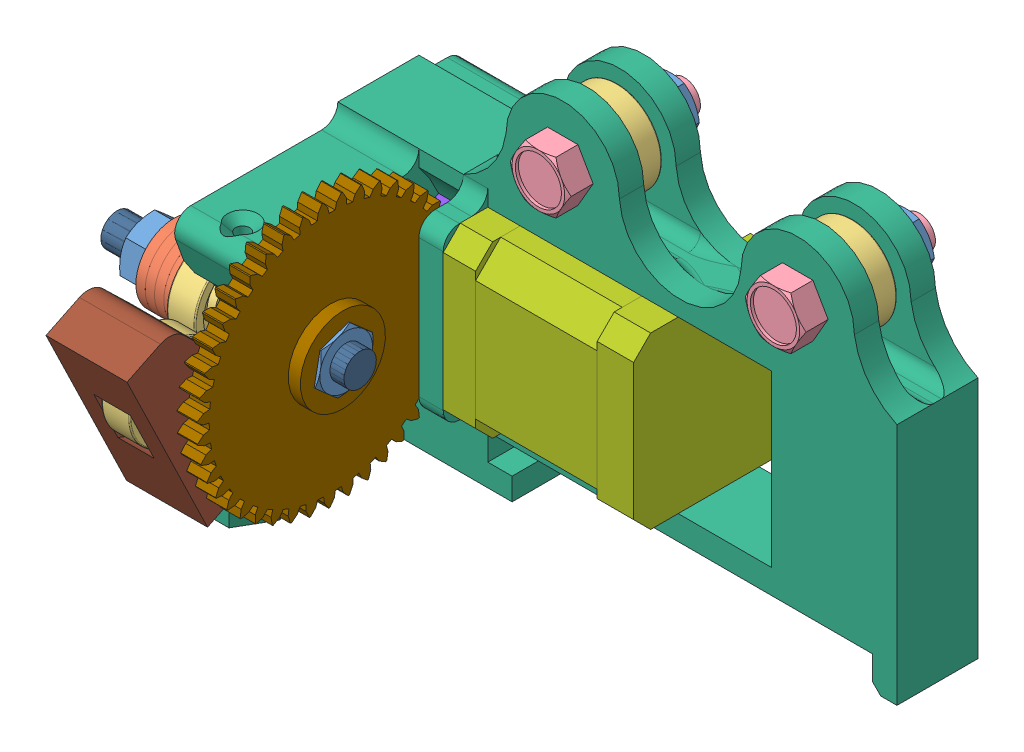
SolidWorks assembly extruder_assy, configuration Défaut. Lengths in mm.
Overall size (163.49 93.45 103.04).
31 component instances, 11 part files, 76 mates.
Components (placement in the parent):
- hex nut style 1_am-1: hex nut style 1_am [B18.2.4.1M - Hex nut, Style 1,  M8 x 1.25 --D-N] at (-59.75 -25 49.5) x (0 0.753756 -0.657154) z (-1 0 0) size (13 15.01 6.8)
- flat washer narrow_am-3: flat washer narrow_am [B18.22M - Plain washer, 8 mm, narrow] at (-88.55 -25 49.5) x (-1 0 0) z (0 0.993598 -0.11297) size (2.3 18.8 18.8)
- flat washer narrow_am-4: flat washer narrow_am [B18.22M - Plain washer, 8 mm, narrow] at (-88.55 -25 49.5) x (1 0 0) z (0 -0.015152 -0.999885) size (2.3 18.8 18.8)
- flat washer narrow_am-5: flat washer narrow_am [B18.22M - Plain washer, 8 mm, narrow] at (-90.85 -25 49.5) x (1 0 0) z (0 -0.015152 -0.999885) size (2.3 18.8 18.8)
- flat washer narrow_am-6: flat washer narrow_am [B18.22M - Plain washer, 8 mm, narrow] at (-93.15 -25 49.5) x (1 0 0) z (0 0.244513 0.969646) size (2.3 18.8 18.8)
- hex nut style 1_am-2: hex nut style 1_am [B18.2.4.1M - Hex nut, Style 1,  M8 x 1.25 --D-N] at (-102.25 -25 49.5) x (0 0.753756 -0.657154) z (-1 0 0) size (13 15.01 6.8)
- instrument ball bearing_68_am-3: instrument ball bearing_68_am [AFBMA 12.1.4.1 - 0080-22 - 8,SI,NC,8_68] at (29 14 10) x (0 0 1) z (-0.516677 0.85618 0) size (7 22 22)
- instrument ball bearing_68_am-4: instrument ball bearing_68_am [AFBMA 12.1.4.1 - 0080-22 - 8,SI,NC,8_68] at (-29 14 10) x (0 0 1) z (0.783647 -0.621206 0) size (7 22 22)
- hex screw_am-1: hex screw_am [B18.6.7M - M8 x 1.25 x 30 Indented HHMS --30N] at (-29 14 26) x (0 0 -1) z (-0.866025 -0.5 0) size (36 15.01 13)
- hex screw_am-2: hex screw_am [B18.6.7M - M8 x 1.25 x 30 Indented HHMS --30N] at (29 14 26) x (0 0 -1) z (0.866025 -0.5 0) size (36 15.01 13)
- hex nut style 1_am-3: hex nut style 1_am [B18.2.4.1M - Hex nut, Style 1,  M8 x 1.25 --D-N] at (-29 14 -6.8) x (0.866025 0.5 0) z (0 0 -1) size (13 15.01 6.8)
- hex nut style 1_am-4: hex nut style 1_am [B18.2.4.1M - Hex nut, Style 1,  M8 x 1.25 --D-N] at (29 14 -6.8) x (0.866025 -0.5 0) z (0 0 -1) size (13 15.01 6.8)
- pan slot head_am-1: pan slot head_am [B18.6.7M - M3 x 0.5 x 10 Slotted PHMS --10N] at (-55.9 -9.5 -5.5) x (1 0 0) z (0 0 -1) size (12.48 5.6 5.6)
- pan slot head_am-2: pan slot head_am [B18.6.7M - M3 x 0.5 x 10 Slotted PHMS --10N] at (-55.9 -9.5 25.5) x (1 0 0) z (0 0 -1) size (12.48 5.6 5.6)
- pan slot head_am-3: pan slot head_am [B18.6.7M - M3 x 0.5 x 10 Slotted PHMS --10N] at (-55.9 -40.5 -5.5) x (1 0 0) z (0 0 -1) size (12.48 5.6 5.6)
- pan slot head_am-4: pan slot head_am [B18.6.7M - M3 x 0.5 x 10 Slotted PHMS --10N] at (-55.9 -40.5 25.5) x (1 0 0) z (0 0 -1) size (12.48 5.6 5.6)
- pan slot head_am-5: pan slot head_am [B18.6.7M - M3 x 0.5 x 8 Slotted PHMS --8N] at (-67.5 -14.272 17.1638) x (0 -0.831627 -0.555335) z (1 0 0) size (10.48 5.6 5.6)
- pan slot head_am-6: pan slot head_am [B18.6.7M - M3 x 0.5 x 8 Slotted PHMS --8N] at (-67.5 -26.408 -2.8229) x (0 0.109148 0.994026) z (1 0 0) size (10.48 5.6 5.6)
- hex nut style 1_am-5: hex nut style 1_am [B18.2.4.1M - Hex nut, Style 1,  M3 x 0.5 --D-N] at (-67.5 -20.0934 13.2765) x (0.973606 0.126747 -0.189807) z (0 0.831627 0.555335) size (5.5 6.35 2.4)
- hex nut style 1_am-6: hex nut style 1_am [B18.2.4.1M - Hex nut, Style 1,  M3 x 0.5 --D-N] at (-67.5 -25.382 6.5209) x (0.518427 -0.850013 0.093335) z (0 0.109148 0.994026) size (5.5 6.35 2.4)
- extruder_spool-1: extruder_spool [Défaut] at origin size (138.49 92 79)
- nema17-1: nema17 [Défaut] at (-47.5 -25 10) x (0 -1 0) z (1 0 0) size (42 42 71)
- extruder_small_gear-1: extruder_small_gear [Défaut] at (-71.5 -25 10) x (1 0 0) z (0 0.109148 0.994026) size (18 18 18)
- extruder_big_gear-1: extruder_big_gear [Défaut] at (-56.75 -25 49.5) x (0 0.981349 -0.192234) z (-1 0 0) size (66 66 9)
- extruder_screw-1: extruder_screw [Défaut] at (-49.5 -25 49.5) x (0 -0.981349 0.192234) z (0 -0.192234 -0.981349) size (8 60 8)
- instrument ball bearing_68_am-1: instrument ball bearing_68_am [AFBMA 12.1.4.1 - 0080-22 - 8,SI,NC,8_68] at (-66.25 -25 49.5) x (1 0 0) z (0 0.940465 0.33989) size (7 22 22)
- instrument ball bearing_68_am-2: instrument ball bearing_68_am [AFBMA 12.1.4.1 - 0080-22 - 8,SI,NC,8_68] at (-82.75 -25 49.5) x (-1 0 0) z (0 0 -1) size (7 22 22)
- instrument ball bearing_68_am-5: instrument ball bearing_68_am [AFBMA 12.1.4.1 - 0080-22 - 8,SI,NC,8_68] at (-74.5 -28.4192 73.8708) x (-1 0 0) z (0 -0.91783 -0.396974) size (7 22 22)
- extruder_tensionner-1: extruder_tensionner [Défaut] at (-64.5 -34.3611 82.1022) x (-1 0 0) z (0 0.436763 -0.899577) size (20 45.5 18)
- pan slot head_am-7: pan slot head_am [B18.6.7M - M3 x 0.5 x 25 Slotted PHMS --25N] at (-62.1 -46 62) x (-1 0 0) z (0 0 1) size (27.48 5.6 5.6)
- hex nut style 1_am-7: hex nut style 1_am [B18.2.4.1M - Hex nut, Style 1,  M3 x 0.5 --D-N] at (-84.5 -46 62) x (0 1 0) z (1 0 0) size (5.5 6.35 2.4)
Mates (geometry in assembly coordinates):
- Coaxiale2: concentric anti-aligned: cylinder of nema17-1 through (-71.5 -25 10) axis (1 0 0) radius 2.5; cylinder of extruder_small_gear-1 through (-53.5 -25 10) axis (-1 0 0) radius 2.65
- Coïncidente2: coincident anti-aligned: plane of extruder_spool-1 through (-53.5 -64 10) normal (-1 0 0); plane of extruder_small_gear-1 through (-53.5 -25 10) normal (1 0 0)
- Coaxiale3: concentric anti-aligned: cylinder of extruder_spool-1 through (53.9891 -25 10) axis (-1 0 0) radius 14; cylinder of nema17-1 through (-49.5 -25 10) axis (1 0 0) radius 11
- Parallèle3: parallel aligned: plane of extruder_spool-1 through (11.897 -4 -11) normal (0 1 0); plane of nema17-1 through (-39.5 -4 -11) normal (0 1 0)
- Coïncidente3: coincident anti-aligned: plane of extruder_spool-1 through (-47.5 -4 -0.001) normal (1 0 0); plane of nema17-1 through (-47.5 -25 10) normal (-1 0 0)
- Parallèle5: parallel aligned: plane of extruder_spool-1 through (-53.5 -64 10) normal (-1 0 0); plane of extruder_big_gear-1 through (-61.75 -25 49.5) normal (-1 0 0)
- Contr.Engrenages2: gear = 18 : 60 mm: circle of extruder_big_gear-1; circle of extruder_small_gear-1
- Coaxiale91: concentric anti-aligned: cylinder of extruder_big_gear-1 through (-61.751 -25 49.5) axis (1 0 0) radius 4.25; cylinder of hex nut style 1_am-1 through (-52.95 -25 49.5) axis (-1 0 0) radius 3.4
- Parallèle12: parallel aligned: plane of extruder_big_gear-1 through (-59.75 -32.3656 50.9428) normal (0 0.94599 0.324195); plane of hex nut style 1_am-1 through (-52.95 -20.0677 55.1574) normal (0 0.94599 0.324195)
- Coïncidente27: coincident anti-aligned: plane of extruder_big_gear-1 through (-59.75 -25 49.5) normal (1 0 0); plane of hex nut style 1_am-1 through (-59.75 -29.9323 43.8426) normal (-1 0 0)
- Coïncidente31: coincident anti-aligned: plane of extruder_big_gear-1; plane of extruder_screw-1
- Coaxiale981: concentric aligned: cylinder of extruder_screw-1 through (-109.5 -25 49.5) axis (1 0 0) radius 4; cylinder of flat washer narrow_am-3 through (-53.625 -25 49.5) axis (1 0 0) radius 4.56
- Coaxiale991: concentric anti-aligned: cylinder of flat washer narrow_am-3 through (-53.625 -25 49.5) axis (1 0 0) radius 9.4; cylinder of flat washer narrow_am-4 through (-123.475 -25 49.5) axis (-1 0 0) radius 4.56
- Coïncidente341: coincident anti-aligned: plane of flat washer narrow_am-3 through (-88.55 -24.4849 54.0308) normal (-1 0 0); plane of flat washer narrow_am-4 through (-88.55 -29.5595 49.5691) normal (1 0 0)
- Coaxiale1001: concentric aligned: cylinder of flat washer narrow_am-4 through (-123.475 -25 49.5) axis (-1 0 0) radius 4.56; cylinder of flat washer narrow_am-5 through (-125.775 -25 49.5) axis (-1 0 0) radius 4.56
- Coïncidente351: coincident anti-aligned: plane of flat washer narrow_am-4 through (-90.85 -34.3989 49.6424) normal (-1 0 0); plane of flat washer narrow_am-5 through (-90.85 -29.5595 49.5691) normal (1 0 0)
- Coaxiale1011: concentric aligned: cylinder of flat washer narrow_am-5 through (-125.775 -25 49.5) axis (-1 0 0) radius 4.56; cylinder of flat washer narrow_am-6 through (-128.075 -25 49.5) axis (-1 0 0) radius 4.56
- Coïncidente361: coincident anti-aligned: plane of flat washer narrow_am-5 through (-93.15 -34.3989 49.6424) normal (-1 0 0); plane of flat washer narrow_am-6 through (-93.15 -20.5784 48.385) normal (1 0 0)
- Coaxiale1021: concentric aligned: cylinder of flat washer narrow_am-6 through (-128.075 -25 49.5) axis (-1 0 0) radius 9.4; cylinder of hex nut style 1_am-2 through (-77.2125 -25 49.5) axis (-1 0 0) radius 4
- Coïncidente371: coincident anti-aligned: plane of flat washer narrow_am-6 through (-95.45 -15.8853 47.2016) normal (-1 0 0); plane of hex nut style 1_am-2 through (-95.45 -29.9323 43.8426) normal (1 0 0)
- Coïncidente38: coincident aligned: plane of hex nut style 1_am-1 through (-52.95 -20.0677 55.1574) normal (0 0.94599 0.324195); plane of hex nut style 1_am-2 through (-95.45 -20.0677 55.1574) normal (0 0.94599 0.324195)
- Coaxiale103: concentric anti-aligned: cylinder of extruder_spool-1 through (-29 14 10.001) axis (0 0 -1) radius 4.2; cylinder of instrument ball bearing_68_am-4 through (-29 14 -10.6375) axis (0 0 1) radius 4
- Coaxiale104: concentric anti-aligned: cylinder of extruder_spool-1 through (29 14 10.001) axis (0 0 -1) radius 4.2; cylinder of instrument ball bearing_68_am-3 through (29 14 -10.6375) axis (0 0 1) radius 4
- Coïncidente39: coincident anti-aligned: plane of extruder_spool-1 through (29 14 6.5) normal (0 0 1); plane of instrument ball bearing_68_am-3 through (34.2227 17.1517 6.5) normal (0 0 -1)
- Coïncidente40: coincident anti-aligned: plane of extruder_spool-1 through (-29 14 6.5) normal (0 0 1); plane of instrument ball bearing_68_am-4 through (-32.7894 9.2198 6.5) normal (0 0 -1)
- Coaxiale106: concentric aligned: cylinder of extruder_spool-1 through (29 14 9.999) axis (0 0 1) radius 4.2; cylinder of hex screw_am-2 through (29 14 51.4) axis (0 0 1) radius 4
- Coïncidente42: coincident anti-aligned: plane of extruder_spool-1 through (0 0 20) normal (0 0 1); plane of hex screw_am-2 through (31 17.4641 20) normal (0 0 -1)
- Coaxiale107: concentric anti-aligned: cylinder of extruder_spool-1 through (-29 14 10.001) axis (0 0 -1) radius 4.2; cylinder of hex screw_am-1 through (-29 14 51.4) axis (0 0 1) radius 4
- Coïncidente43: coincident anti-aligned: plane of extruder_spool-1 through (0 0 20) normal (0 0 1); plane of hex screw_am-1 through (-27 10.5359 20) normal (0 0 -1)
- Parallèle13: parallel aligned: plane of hex screw_am-1 through (-25.2472 20.5 20) normal (0 1 0); plane of hex screw_am-2 through (32.7528 20.5 20) normal (0 1 0)
- Parallèle14: parallel aligned: plane of extruder_spool-1 through (-47.5 -46 -0.001) normal (0 1 0); plane of hex screw_am-1 through (-25.2472 20.5 20) normal (0 1 0)
- Coaxiale108: concentric anti-aligned: cylinder of hex screw_am-1 through (-29 14 51.4) axis (0 0 1) radius 4; cylinder of hex nut style 1_am-3 through (-29 14 18.2375) axis (0 0 -1) radius 4
- Coïncidente44: coincident anti-aligned: plane of extruder_spool-1 through (0 0 0) normal (0 0 -1); plane of hex nut style 1_am-3 through (-25.2472 7.5 0) normal (0 0 1)
- Coaxiale109: concentric anti-aligned: cylinder of hex screw_am-2 through (29 14 51.4) axis (0 0 1) radius 4; cylinder of hex nut style 1_am-4 through (29 14 18.2375) axis (0 0 -1) radius 4
- Coïncidente45: coincident anti-aligned: plane of extruder_spool-1 through (0 0 0) normal (0 0 -1); plane of hex nut style 1_am-4 through (25.2472 7.5 0) normal (0 0 1)
- Parallèle15: parallel aligned: plane of hex nut style 1_am-3 through (-32.7528 20.5 0) normal (0 1 0); plane of hex nut style 1_am-4 through (25.2472 20.5 0) normal (0 1 0)
- Parallèle16: parallel aligned: plane of hex screw_am-2 through (32.7528 20.5 20) normal (0 1 0); plane of hex nut style 1_am-4 through (25.2472 20.5 0) normal (0 1 0)
- Coaxiale1026: concentric anti-aligned: cone of nema17-1 through (-47.3 -9.5 -5.5) axis (1 0 0); cylinder of pan slot head_am-1 through (-81.3 -9.5 -5.5) axis (-1 0 0) radius 2.8
- Coïncidente384: coincident anti-aligned: plane of extruder_spool-1 through (-53.5 -64 10) normal (-1 0 0); plane of pan slot head_am-1 through (-53.5 -11 -5.5) normal (1 0 0)
- Coaxiale1027: concentric aligned: cylinder of extruder_spool-1 through (53.9891 -9.5 25.5) axis (-1 0 0) radius 2; cylinder of pan slot head_am-2 through (-81.3 -9.5 25.5) axis (-1 0 0) radius 1.5
- Coaxiale1028: concentric aligned: cylinder of extruder_spool-1 through (53.9891 -40.5 -5.5) axis (-1 0 0) radius 2; cylinder of pan slot head_am-3 through (-81.3 -40.5 -5.5) axis (-1 0 0) radius 1.5
- Coaxiale1029: concentric aligned: cylinder of extruder_spool-1 through (53.9891 -40.5 25.5) axis (-1 0 0) radius 2; cylinder of pan slot head_am-4 through (-81.3 -40.5 25.5) axis (-1 0 0) radius 1.5
- Coïncidente385: coincident anti-aligned: plane of extruder_spool-1 through (-53.5 -64 10) normal (-1 0 0); plane of pan slot head_am-3 through (-53.5 -42 -5.5) normal (1 0 0)
- Coïncidente386: coincident anti-aligned: plane of extruder_spool-1 through (-53.5 -64 10) normal (-1 0 0); plane of pan slot head_am-4 through (-53.5 -42 25.5) normal (1 0 0)
- Coïncidente387: coincident anti-aligned: plane of extruder_spool-1 through (-53.5 -64 10) normal (-1 0 0); plane of pan slot head_am-2 through (-53.5 -11 25.5) normal (1 0 0)
- Parallèle19: parallel aligned: line of pan slot head_am-1 through (-55.9 -9 -3.9801) axis (0 0 -1); line of pan slot head_am-2 through (-55.9 -9 27.0199) axis (0 0 -1)
- Parallèle20: parallel anti-aligned: line of pan slot head_am-3 through (-55.9 -41 -7.0199) axis (0 0 1); line of pan slot head_am-4 through (-55.9 -40 27.0199) axis (0 0 -1)
- Parallèle21: parallel aligned: line of pan slot head_am-2 through (-55.9 -10 23.9801) axis (0 0 1); line of pan slot head_am-4 through (-55.9 -41 23.9801) axis (0 0 1)
- Parallèle22: parallel anti-aligned: line of extruder_spool-1 through (-84.5 -4 24) axis (0 0 1); line of pan slot head_am-2 through (-55.9 -9 27.0199) axis (0 0 -1)
- Coaxiale1030: concentric aligned: cylinder of extruder_small_gear-1 through (-67.5 -25 10) axis (0 0.831627 0.555335) radius 2; cylinder of pan slot head_am-5 through (-67.5 6.8513 31.2693) axis (0 0.831627 0.555335) radius 2.8
- Tangent1: tangent anti-aligned: cylinder of nema17-1 through (-71.5 -25 10) axis (1 0 0) radius 2.5; plane of pan slot head_am-5 through (-67.5 -22.0879 10.1409) normal (0 -0.831627 -0.555335)
- Coaxiale1032: concentric aligned: cylinder of extruder_small_gear-1 through (-67.5 -25 10) axis (0 -0.109148 -0.994026) radius 2; cylinder of pan slot head_am-6 through (-67.5 -29.1804 -28.0712) axis (0 -0.109148 -0.994026) radius 1.5
- Tangent2: tangent anti-aligned: cylinder of nema17-1 through (-71.5 -25 10) axis (1 0 0) radius 2.5; plane of pan slot head_am-6 through (-67.5 -26.7639 7.6787) normal (0 0.109148 0.994026)
- Coïncidente388: coincident anti-aligned: plane of extruder_small_gear-1 through (-64.5 -23.7553 14.4386) normal (0 0.831627 0.555335); plane of hex nut style 1_am-5 through (-68.2247 -20.3724 9.3726) normal (0 -0.831627 -0.555335)
- Coaxiale1033: concentric anti-aligned: cylinder of pan slot head_am-6 through (-67.5 -29.1804 -28.0712) axis (0 -0.109148 -0.994026) radius 1.5; cylinder of hex nut style 1_am-6 through (-67.5 -25.644 4.1352) axis (0 0.109148 0.994026) radius 1.25
- Coaxiale1034: concentric aligned: cylinder of pan slot head_am-5 through (-67.5 6.8513 31.2693) axis (0 0.831627 0.555335) radius 1.5; cylinder of hex nut style 1_am-5 through (-67.5 -22.0893 11.9437) axis (0 0.831627 0.555335) radius 1.25
- Coïncidente389: coincident anti-aligned: plane of extruder_small_gear-1 through (-64.5 -22.3999 6.1935) normal (0 -0.109148 -0.994026); plane of hex nut style 1_am-6 through (-64.7846 -23.7456 6.3412) normal (0 0.109148 0.994026)
- Coaxiale1035: concentric aligned: cylinder of extruder_spool-1 through (-78.25 -25 49.5) axis (1 0 0) radius 4.25; cylinder of extruder_screw-1 through (-109.5 -25 49.5) axis (1 0 0) radius 4
- Coïncidente392: coincident anti-aligned: plane of extruder_spool-1 through (-79.25 0 0) normal (-1 0 0); plane of instrument ball bearing_68_am-2 through (-79.25 -18.9 49.5) normal (1 0 0)
- Coaxiale1036: concentric anti-aligned: cylinder of extruder_screw-1 through (-109.5 -25 49.5) axis (1 0 0) radius 4; cylinder of instrument ball bearing_68_am-2 through (-62.1125 -25 49.5) axis (-1 0 0) radius 4
- Coïncidente393: coincident anti-aligned: plane of extruder_spool-1 through (-69.75 0 0) normal (1 0 0); plane of instrument ball bearing_68_am-1 through (-69.75 -22.9267 43.7632) normal (-1 0 0)
- Coaxiale1037: concentric aligned: cylinder of extruder_screw-1 through (-109.5 -25 49.5) axis (1 0 0) radius 4; cylinder of instrument ball bearing_68_am-1 through (-86.8875 -25 49.5) axis (1 0 0) radius 4
- Coïncidente396: coincident aligned: plane of extruder_spool-1 through (-84.5 0 0) normal (-1 0 0); plane of extruder_tensionner-1 through (-84.5 -34.3611 82.1022) normal (-1 0 0)
- Coïncidente397: coincident anti-aligned: plane of extruder_big_gear-1 through (-62.75 -25 49.5) normal (-1 0 0); plane of instrument ball bearing_68_am-1 through (-62.75 -23.5385 45.456) normal (1 0 0)
- Coïncidente398: coincident anti-aligned: plane of flat washer narrow_am-3 through (-86.25 -23.9381 58.8398) normal (1 0 0); plane of instrument ball bearing_68_am-2 through (-86.25 -20.7 49.5) normal (-1 0 0)
- Coaxiale1041: concentric anti-aligned: cylinder of extruder_spool-1 through (-58.8431 -46 62) axis (-1 0 0) radius 2; cylinder of extruder_tensionner-1 through (-84.501 -46 62) axis (1 0 0) radius 2
- Coïncidente399: coincident anti-aligned: plane of instrument ball bearing_68_am-5 through (-78 -26.7122 69.9241) normal (-1 0 0); plane of extruder_tensionner-1 through (-78 -34.3611 82.1022) normal (1 0 0)
- Coaxiale1043: concentric anti-aligned: cylinder of instrument ball bearing_68_am-5 through (-53.8625 -28.4192 73.8708) axis (-1 0 0) radius 4; cylinder of extruder_tensionner-1 through (-81.5 -28.4192 73.8708) axis (1 0 0) radius 4.25
- Parallèle28: parallel aligned: line of pan slot head_am-5 through (-69.0199 -14.5497 17.5796) axis (1 0 0); line of pan slot head_am-6 through (-69.0199 -25.911 -2.8775) axis (1 0 0)
- Coaxiale1044: concentric anti-aligned: cylinder of extruder_spool-1 through (-58.8431 -46 62) axis (-1 0 0) radius 2; cylinder of pan slot head_am-7 through (-36.7 -46 62) axis (1 0 0) radius 2.8
- Coïncidente400: coincident anti-aligned: plane of extruder_spool-1 through (-64.5 0 0) normal (1 0 0); plane of pan slot head_am-7 through (-64.5 -47.5 62) normal (-1 0 0)
- Coaxiale1045: concentric aligned: cylinder of pan slot head_am-7 through (-36.7 -46 62) axis (1 0 0) radius 1.5; cylinder of hex nut style 1_am-7 through (-109.5375 -46 62) axis (1 0 0) radius 1.5
- Parallèle29: parallel: line of pan slot head_am-7 through (-62.1 -45.5 60.4801) axis (0 0 1); plane of hex nut style 1_am-7 through (-86.9 -48.75 63.5877) normal (0 -1 0)
- Parallèle30: parallel aligned: line of extruder_spool-1 through (-64.5 -46 20) axis (0 0 1); line of pan slot head_am-7 through (-62.1 -45.5 60.4801) axis (0 0 1)
- Coïncidente401: coincident anti-aligned: plane of extruder_spool-1 through (-84.5 0 0) normal (-1 0 0); plane of hex nut style 1_am-7 through (-84.5 -46 65.1754) normal (1 0 0)
- Distance1: distance = 25 mm aligned: plane of extruder_screw-1 through (-109.5 -25 49.5) normal (-1 0 0); plane of extruder_spool-1 through (-84.5 0 0) normal (-1 0 0)
